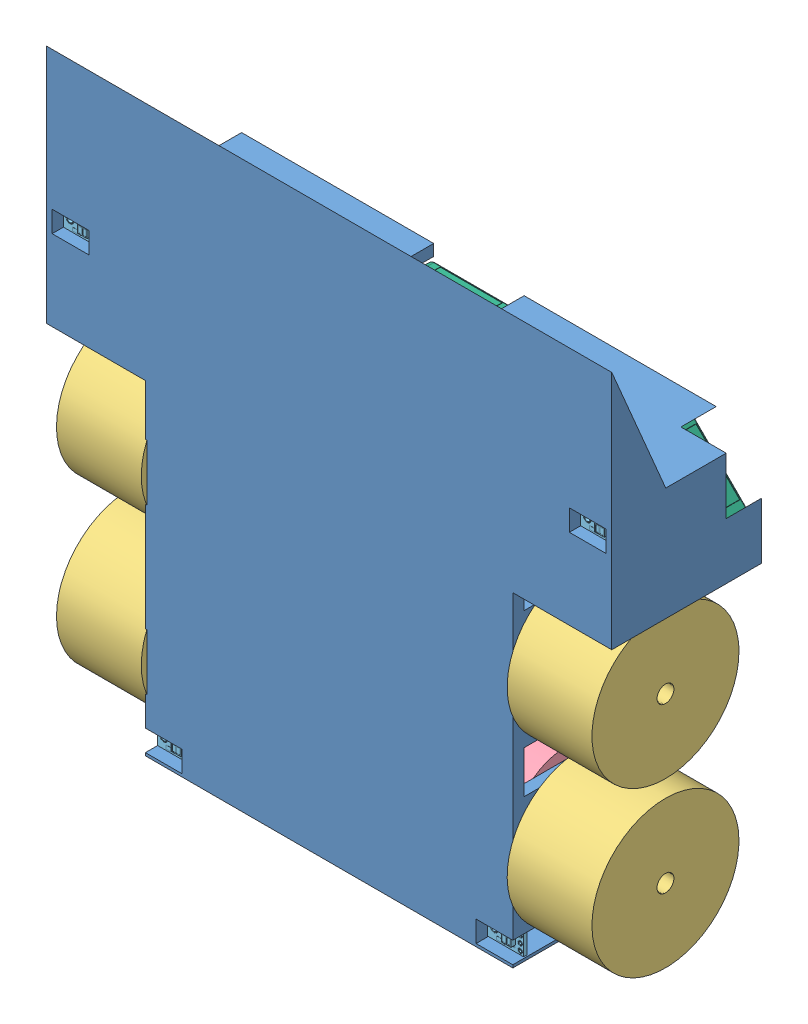
SolidWorks assembly AssemblySumoModif, configuration Default. Lengths in mm.
Overall size (200 203.77 71.84).
46 component instances, 13 part files, 37 mates.
Components (placement in the parent):
- Body3-1: Body3 [Predeterminado] at (6.5509 9.0272 156.0225) size (200 200 53)
- Body4-1: Body4 [Predeterminado] at (7.0509 8.0272 156.0225) size (129.95 98 1)
- Llantita-1: Llantita [Default] at (171.5509 96.0272 136.0225) x (0 0.069349 -0.997592) z (1 0 0) size (52 52 30)
- Titan-37mm-500rpm.stp-1: Titan-37mm-500rpm.stp [Default] at (146.0509 44.867 137.5225) x (0 0.214215 -0.976786) z (1 0 0) size (37.72 37.72 78.76)
- Titan-37mm-500rpm.stp-2: Titan-37mm-500rpm.stp [Default] at (67.6013 44.867 137.5225) x (0 -0.214215 0.976786) z (-1 0 0) size (37.72 37.72 78.76)
- Titan-37mm-500rpm.stp-3: Titan-37mm-500rpm.stp [Default] at (67.6013 102.867 137.5225) x (0 -0.214215 0.976786) z (-1 0 0) size (37.72 37.72 78.76)
- Titan-37mm-500rpm.stp-4: Titan-37mm-500rpm.stp [Default] at (146.0509 102.867 137.5225) x (0 0.214215 -0.976786) z (1 0 0) size (37.72 37.72 78.76)
- Llantita-2: Llantita [Default] at (171.5509 38.0272 136.0225) x (0 0.139027 -0.990289) z (1 0 0) size (52 52 30)
- Llantita-3: Llantita [Default] at (42.1013 96.0272 136.0225) x (0 0.539892 0.841734) z (-1 0 0) size (52 52 30)
- Llantita-4: Llantita [Default] at (42.1013 38.0272 136.0225) x (0 0.309754 0.950817) z (-1 0 0) size (52 52 30)
- pololu-QTR-1a-1: pololu-QTR-1a [Predeterminado] at (191.5509 152.5272 154.8825) size (12.8 7.17 2.73)
- pololu-QTR-1a-2: pololu-QTR-1a [Predeterminado] at (158.5509 10.3572 154.8825) size (12.8 7.17 2.73)
- pololu-QTR-1a-3: pololu-QTR-1a [Predeterminado] at (41.7509 10.3572 154.8825) size (12.8 7.17 2.73)
- pololu-QTR-1a-4: pololu-QTR-1a [Predeterminado] at (8.5509 152.5272 154.8825) size (12.8 7.17 2.73)
- Pepperl-Fuchs-ML100-8-1000-RT.stp-1: Pepperl-Fuchs-ML100-8-1000-RT.stp [Default] at (25.5626 150.4591 114.0225) x (0 0 1) z (0.72862 0.684918 0) size (11.02 23.57 34.55)
- Pepperl-Fuchs-ML100-8-1000-RT.stp-2: Pepperl-Fuchs-ML100-8-1000-RT.stp [Default] at (111.3509 157.193 114.1297) x (0 0.039326 0.999226) z (1 0 0) size (11.02 23.57 34.55)
- Pepperl-Fuchs-ML100-8-1000-RT.stp-3: Pepperl-Fuchs-ML100-8-1000-RT.stp [Default] at (194.8204 143.6359 114.0225) x (0 0 1) z (0.707107 -0.707107 0) size (11.02 23.57 34.55)
- uploads_b4_22_56_eb_53_Arduino.ipt.stp-1: uploads_b4_22_56_eb_53_Arduino.ipt.stp [Default] at (79.1243 84.4444 116.0225) x (0 1 0) z (-1 0 0) size (74.93 14.99 53.34)
- node-1824x-cad.step-1: node-1824x-cad.step [Default] at (9.5017 79.2417 114.4225) x (-0.999965 0.008331 0) z (0 0 -1) size (30 50 7.5)
  - Board.step-1: Board.step [Default] at origin size (30 50 1.6)
  - capae-6.6x6.6h5.7.step-1: capae-6.6x6.6h5.7.step [Default] at (-55.5301 -11.5859 0) x (0 -1 0) z (0 0 1) size (6.64 6.64 5.89)
  - capae-6.6x6.6h5.7.step-2: capae-6.6x6.6h5.7.step [Default] at (-39.9374 -11.3677 0) x (0 -1 0) z (0 0 1) size (6.64 6.64 5.89)
  - dio_0805.step-1: dio_0805.step [Default] at (-40.8591 -36.3956 0) x (-1 0 0) z (0 0 1) size (2.04 1.28 1.28)
  - dio_0805.step-2: dio_0805.step [Default] at (-40.8591 -33.6079 0) x (-1 0 0) z (0 0 1) size (2.04 1.28 1.28)
  - dio_0805.step-3: dio_0805.step [Default] at (-40.8591 -30.8201 0) x (-1 0 0) z (0 0 1) size (2.04 1.28 1.28)
  - dio_0805.step-4: dio_0805.step [Default] at (-40.3443 -22.7571 0) x (-1 0 0) z (0 0 1) size (2.04 1.28 1.28)
  - to252-3_9.6x6.6x2.28.step-1: to252-3_9.6x6.6x2.28.step [Default] at (-47.7789 -14.8338 0) x (-1 0 0) z (0 0 1) size (7.65 12.33 2.63)
  - res_0805.step-1: res_0805.step [Default] at (-45.9391 -36.3956 0) x (-1 0 0) z (0 0 1) size (2.04 1.28 0.32)
  - res_0805.step-2: res_0805.step [Default] at (-45.9391 -33.6079 0) x (-1 0 0) z (0 0 1) size (2.04 1.28 0.32)
  - res_0805.step-3: res_0805.step [Default] at (-45.9391 -30.8201 0) x (-1 0 0) z (0 0 1) size (2.04 1.28 0.32)
  - res_0805.step-4: res_0805.step [Default] at (-40.2785 -20.5814 0) x (-1 0 0) z (0 0 1) size (2.04 1.28 0.32)
  - tssop-14.step-1: tssop-14.step [Default] at (-54.0357 -30.6644 0) x (0 1 0) z (0 0 1) size (5.29 6.86 1.33)
- node-1824x-cad.step-2: node-1824x-cad.step [Default] at (101.74 79.5651 114.4225) x (-1 -0.000396 0) z (0 0 -1) size (30 50 7.5)
  - Board.step-1: Board.step [Default] at origin size (30 50 1.6)
  - capae-6.6x6.6h5.7.step-1: capae-6.6x6.6h5.7.step [Default] at (-55.5301 -11.5859 0) x (0 -1 0) z (0 0 1) size (6.64 6.64 5.89)
  - capae-6.6x6.6h5.7.step-2: capae-6.6x6.6h5.7.step [Default] at (-39.9374 -11.3677 0) x (0 -1 0) z (0 0 1) size (6.64 6.64 5.89)
  - dio_0805.step-1: dio_0805.step [Default] at (-40.8591 -36.3956 0) x (-1 0 0) z (0 0 1) size (2.04 1.28 1.28)
  - dio_0805.step-2: dio_0805.step [Default] at (-40.8591 -33.6079 0) x (-1 0 0) z (0 0 1) size (2.04 1.28 1.28)
  - dio_0805.step-3: dio_0805.step [Default] at (-40.8591 -30.8201 0) x (-1 0 0) z (0 0 1) size (2.04 1.28 1.28)
  - dio_0805.step-4: dio_0805.step [Default] at (-40.3443 -22.7571 0) x (-1 0 0) z (0 0 1) size (2.04 1.28 1.28)
  - to252-3_9.6x6.6x2.28.step-1: to252-3_9.6x6.6x2.28.step [Default] at (-47.7789 -14.8338 0) x (-1 0 0) z (0 0 1) size (7.65 12.33 2.63)
  - res_0805.step-1: res_0805.step [Default] at (-45.9391 -36.3956 0) x (-1 0 0) z (0 0 1) size (2.04 1.28 0.32)
  - res_0805.step-2: res_0805.step [Default] at (-45.9391 -33.6079 0) x (-1 0 0) z (0 0 1) size (2.04 1.28 0.32)
  - res_0805.step-3: res_0805.step [Default] at (-45.9391 -30.8201 0) x (-1 0 0) z (0 0 1) size (2.04 1.28 0.32)
  - res_0805.step-4: res_0805.step [Default] at (-40.2785 -20.5814 0) x (-1 0 0) z (0 0 1) size (2.04 1.28 0.32)
  - tssop-14.step-1: tssop-14.step [Default] at (-54.0357 -30.6644 0) x (0 1 0) z (0 0 1) size (5.29 6.86 1.33)
Mates (geometry in assembly coordinates):
- Concentric1: concentric: cylinder of assembly; cylinder of assembly; cylinder of Body3-1 through (36.5509 96.0272 136.0225) axis (1 0 0) radius 6; cylinder of Titan-37mm-500rpm.stp-4 through (167.5509 96.0272 136.0225) axis (1 0 0) radius 6
- Coincident1: coincident: plane of assembly; plane of assembly; plane of Body3-1 through (167.5509 116.5272 117.0225) normal (-1 0 0); plane of Titan-37mm-500rpm.stp-4 through (167.5509 102.867 137.5225) normal (1 0 0)
- Concentric2: concentric: cylinder of assembly; cylinder of assembly; cylinder of Body3-1 through (36.5509 38.0272 136.0225) axis (1 0 0) radius 6; cylinder of Titan-37mm-500rpm.stp-1 through (167.5509 38.0272 136.0225) axis (1 0 0) radius 6
- Coincident2: coincident: plane of assembly; plane of assembly; plane of Body3-1 through (167.5509 116.5272 117.0225) normal (-1 0 0); plane of Titan-37mm-500rpm.stp-1 through (167.5509 44.867 137.5225) normal (1 0 0)
- Tangent1: tangent: plane of assembly; cylinder of assembly; plane of Body3-1 through (6.5509 9.0272 156.0225) normal (0 0 -1); cylinder of Titan-37mm-500rpm.stp-4 through (146.0509 102.867 137.5225) axis (1 0 0) radius 18.5
- Concentric3: concentric: cylinder of assembly; cylinder of assembly; cylinder of Body3-1 through (36.5509 38.0272 136.0225) axis (1 0 0) radius 6; cylinder of Titan-37mm-500rpm.stp-2 through (46.1013 38.0272 136.0225) axis (-1 0 0) radius 6
- Coincident4: coincident: plane of assembly; plane of assembly; plane of Body3-1 through (46.1013 116.5272 117.0225) normal (1 0 0); plane of Titan-37mm-500rpm.stp-2 through (46.1013 44.867 137.5225) normal (-1 0 0)
- Tangent2: tangent: plane of assembly; cylinder of assembly; plane of Body3-1 through (6.5509 9.0272 156.0225) normal (0 0 -1); cylinder of Titan-37mm-500rpm.stp-1 through (146.0509 44.867 137.5225) axis (1 0 0) radius 18.5
- Tangent3: tangent: plane of assembly; cylinder of assembly; plane of Body3-1 through (6.5509 9.0272 156.0225) normal (0 0 -1); cylinder of Titan-37mm-500rpm.stp-2 through (67.6013 44.867 137.5225) axis (-1 0 0) radius 18.5
- Concentric4: concentric: cylinder of assembly; cylinder of assembly; cylinder of Body3-1 through (36.5509 96.0272 136.0225) axis (1 0 0) radius 6; cylinder of Titan-37mm-500rpm.stp-3 through (46.1013 96.0272 136.0225) axis (-1 0 0) radius 6
- Coincident5: coincident: plane of assembly; plane of assembly; plane of Body3-1 through (46.1013 116.5272 117.0225) normal (1 0 0); plane of Titan-37mm-500rpm.stp-3 through (46.1013 102.867 137.5225) normal (-1 0 0)
- Tangent4: tangent: plane of assembly; cylinder of assembly; plane of Body3-1 through (6.5509 9.0272 156.0225) normal (0 0 -1); cylinder of Titan-37mm-500rpm.stp-3 through (67.6013 102.867 137.5225) axis (-1 0 0) radius 18.5
- Concentric5: concentric: cylinder of assembly; cylinder of assembly; cylinder of Titan-37mm-500rpm.stp-1 through (173.5509 38.0272 136.0225) axis (1 0 0) radius 3; cylinder of Llantita-2 through (201.5509 38.0272 136.0225) axis (-1 0 0) radius 3
- Coincident6: coincident: plane of assembly; plane of assembly; plane of Body3-1 through (171.5509 9.0272 160.0225) normal (1 0 0); plane of Llantita-2 through (171.5509 38.0272 136.0225) normal (-1 0 0)
- Concentric6: concentric: cylinder of assembly; cylinder of assembly; cylinder of Llantita-1 through (201.5509 96.0272 136.0225) axis (-1 0 0) radius 3; cylinder of Titan-37mm-500rpm.stp-4 through (173.5509 96.0272 136.0225) axis (1 0 0) radius 3
- Coincident7: coincident: plane of assembly; plane of assembly; plane of Body3-1 through (171.5509 9.0272 160.0225) normal (1 0 0); plane of Llantita-1 through (171.5509 96.0272 136.0225) normal (-1 0 0)
- Concentric7: concentric: cylinder of assembly; cylinder of assembly; cylinder of Titan-37mm-500rpm.stp-3 through (40.1013 96.0272 136.0225) axis (-1 0 0) radius 3; cylinder of Llantita-3 through (12.1013 96.0272 136.0225) axis (1 0 0) radius 3
- Coincident8: coincident: plane of assembly; plane of assembly; plane of Body3-1 through (42.1013 116.5272 117.0225) normal (-1 0 0); plane of Llantita-3 through (42.1013 96.0272 136.0225) normal (1 0 0)
- Concentric8: concentric: cylinder of assembly; cylinder of assembly; cylinder of Titan-37mm-500rpm.stp-2 through (40.1013 38.0272 136.0225) axis (-1 0 0) radius 3; cylinder of Llantita-4 through (12.1013 38.0272 136.0225) axis (1 0 0) radius 3
- Coincident9: coincident: plane of assembly; plane of assembly; plane of Body3-1 through (42.1013 116.5272 117.0225) normal (-1 0 0); plane of Llantita-4 through (42.1013 38.0272 136.0225) normal (1 0 0)
- Coincident10: coincident: line of assembly; line of assembly; line of Body3-1 through (42.1013 116.5272 117.0225) axis (0 -1 0); line of Body4-1 through (42.1013 17.5272 117.0225) axis (0 1 0)
- Coincident11: coincident: line of assembly; line of assembly; line of Body3-1 through (42.1013 17.5272 117.0225) axis (1 0 0); line of Body4-1 through (172.0509 17.5272 117.0225) axis (-1 0 0)
- Coincident12: coincident: line of assembly; line of assembly; line of Body3-1 through (204.5509 152.5272 156.0225) axis (-1 0 0); line of pololu-QTR-1a-1 through (191.5509 152.5272 156.0225) axis (1 0 0)
- Coincident13: coincident: plane of assembly; plane of assembly; plane of Body3-1 through (191.5509 160.0272 166.0225) normal (1 0 0); plane of pololu-QTR-1a-1 through (191.5509 152.5272 156.0225) normal (-1 0 0)
- Coincident14: coincident: line of assembly; line of assembly; line of Body3-1 through (8.5509 152.5272 156.0225) axis (1 0 0); line of pololu-QTR-1a-4 through (8.5509 152.5272 156.0225) axis (1 0 0)
- Coincident15: coincident: plane of assembly; plane of assembly; plane of Body3-1 through (8.5509 160.0272 107.0225) normal (1 0 0); plane of pololu-QTR-1a-4 through (8.5509 152.5272 156.0225) normal (-1 0 0)
- Coincident16: coincident: line of assembly; line of assembly; line of Body3-1 through (158.5509 17.5272 156.0225) axis (1 0 0); line of pololu-QTR-1a-2 through (171.3509 17.5272 156.0225) axis (-1 0 0)
- Coincident17: coincident: plane of assembly; plane of assembly; plane of Body3-1 through (158.5509 10.0272 166.0225) normal (1 0 0); plane of pololu-QTR-1a-2 through (158.5509 10.3572 156.0225) normal (-1 0 0)
- Coincident18: coincident: line of assembly; line of assembly; line of Body3-1 through (46.1013 17.5272 156.0225) axis (1 0 0); line of pololu-QTR-1a-3 through (54.5509 17.5272 156.0225) axis (-1 0 0)
- Coincident19: coincident: plane of assembly; plane of assembly; plane of Body3-1 through (54.5509 10.0272 166.0225) normal (-1 0 0); plane of pololu-QTR-1a-3 through (54.5509 10.3572 156.0225) normal (1 0 0)
- Coincident21: coincident: line of assembly; line of assembly; line of Body3-1 through (122.5509 160.0272 119.5225) axis (-1 0 0); line of Pepperl-Fuchs-ML100-8-1000-RT.stp-2 through (92.5509 160.0272 119.5225) axis (1 0 0)
- Coincident22: coincident: plane of assembly; plane of assembly; plane of Body3-1 through (90.5509 144.0272 119.5225) normal (1 0 0); plane of Pepperl-Fuchs-ML100-8-1000-RT.stp-2 through (90.5509 160.5268 119.5028) normal (-1 0 0)
- Coincident30: coincident: plane of assembly; plane of assembly; plane of Body3-1 through (-5.5912 156.1277 119.5225) normal (0 0 -1); plane of Pepperl-Fuchs-ML100-8-1000-RT.stp-1 through (30.8576 159.7185 119.5225) normal (0 0 1)
- Coincident31: coincident: plane of assembly; plane of assembly; plane of Body4-1 through (7.0509 8.0272 116.0225) normal (0 0 -1); plane of uploads_b4_22_56_eb_53_Arduino.ipt.stp-1 through (105.6658 51.9974 116.0225) normal (0 0 1)
- Coincident32: coincident: plane of assembly; plane of assembly; plane of Body4-1 through (7.0509 8.0272 116.0225) normal (0 0 -1); plane of node-1824x-cad.step-1/Board.step-1 through (72.0792 28.0541 116.0225) normal (0 0 1)
- Coincident33: coincident: plane of assembly; plane of assembly; plane of Body4-1 through (7.0509 8.0272 116.0225) normal (0 0 -1); plane of node-1824x-cad.step-2/Board.step-1 through (164.7618 28.9256 116.0225) normal (0 0 1)
- Coincident34: coincident: plane of assembly; plane of assembly; plane of Body3-1 through (200.6514 174.1694 119.5225) normal (0 0 -1); plane of Pepperl-Fuchs-ML100-8-1000-RT.stp-3 through (204.2391 138.6296 119.5225) normal (0 0 1)
